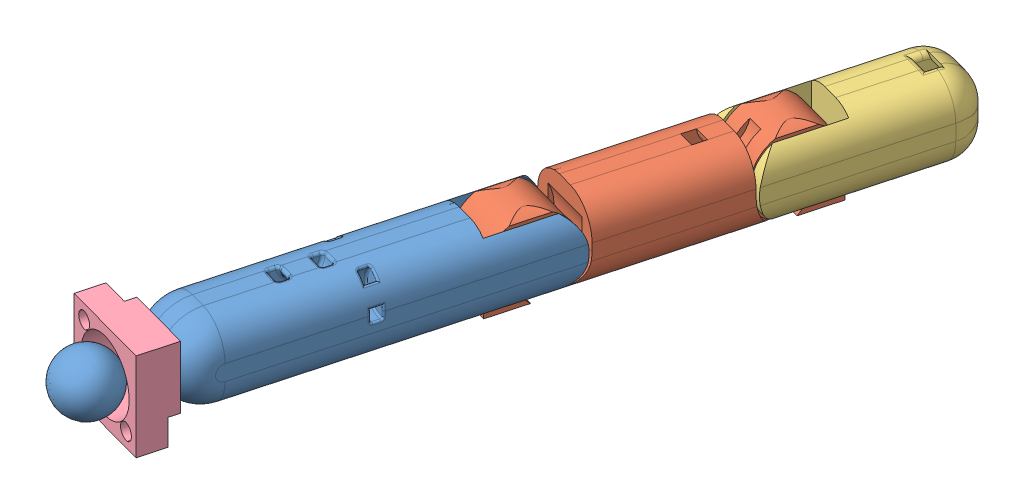
SolidWorks assembly thumb_printable, configuration Default. Lengths in mm.
Overall size (52.39 17 142.38).
4 component instances, 4 part files, 7 mates.
Components (placement in the parent):
- Metacarpal Bone_V02_thumb-1: Metacarpal Bone_V02_thumb [Default] at (0.84 8.5 18.7297) x (0.264255 0 -0.964453) z (0.964453 0 0.264255) size (80.05 15 15)
- Proximal Phalanx Bone_V02-1: Proximal Phalanx Bone_V02 [Default] at (13.9206 8.5 -29.0108) x (0.264255 0 -0.964453) z (0.964453 0 0.264255) size (56.6 15.07 15)
- Distal Phalanx Bone_V02-1: Distal Phalanx Bone_V02 [Default] at (34.6646 8.5 -104.7203) x (-0.264255 0 0.964453) z (-0.964453 0 -0.264255) size (36.8 15 15)
- thumb_ball_joint_cap-1: thumb_ball_joint_cap [Default] at (-0.7655 8.5 24.5891) x (-0.964453 0 -0.264255) z (0.264255 0 -0.964453) size (17 17 7)
Mates (geometry in assembly coordinates):
- Coincident6: coincident anti-aligned: plane of thumb_ball_joint_cap-1 through (0.0273 0 21.6957) normal (0 -1 0)
- Concentric4: concentric: cylinder of Metacarpal Bone_V02_thumb-1 through (-1.807 8.5 28.3903) axis (0.264255 0 -0.964453) radius 1.5; circle of thumb_ball_joint_cap-1
- Parallel4: parallel aligned: plane of Metacarpal Bone_V02_thumb-1 through (10.651 7 -45.4595) normal (-0.964453 0 -0.264255); plane of thumb_ball_joint_cap-1 through (-8.1706 8.5 19.4495) normal (-0.964453 0 -0.264255)
- Concentric5: concentric anti-aligned: cylinder of Metacarpal Bone_V02_thumb-1 through (9.2478 8.5 -38.0675) axis (0.964453 0 0.264255) radius 2.5; cylinder of Proximal Phalanx Bone_V02-1 through (21.9785 8.5 -34.5794) axis (-0.964453 0 -0.264255) radius 3.4
- Width3: width aligned: plane of Proximal Phalanx Bone_V02-1 through (9.3876 8.5 -30.2528) normal (-0.964453 0 -0.264255); plane of Proximal Phalanx Bone_V02-1 through (18.4535 8.5 -27.7688) normal (0.964453 0 0.264255); plane of Metacarpal Bone_V02_thumb-1 through (5.7587 1 20.0774) normal (-0.964453 0 -0.264255); plane of Metacarpal Bone_V02_thumb-1 through (-4.0788 1 17.382) normal (0.964453 0 0.264255)
- Concentric6: concentric aligned: cylinder of Proximal Phalanx Bone_V02-1 through (32.998 8.5 -74.797) axis (-0.964453 0 -0.264255) radius 3.4; cylinder of Distal Phalanx Bone_V02-1 through (33.7695 8.5 -74.5856) axis (-0.964453 0 -0.264255) radius 2.5
- Width4: width anti-aligned: plane of Distal Phalanx Bone_V02-1 through (29.7459 1 -106.068) normal (0.964453 0 0.264255); plane of Distal Phalanx Bone_V02-1 through (39.5833 1 -103.3726) normal (-0.964453 0 -0.264255); plane of Proximal Phalanx Bone_V02-1 through (24.3709 8.5 -84.9372) normal (-0.964453 0 -0.264255); plane of Proximal Phalanx Bone_V02-1 through (33.4367 8.5 -82.4532) normal (0.964453 0 0.264255)
